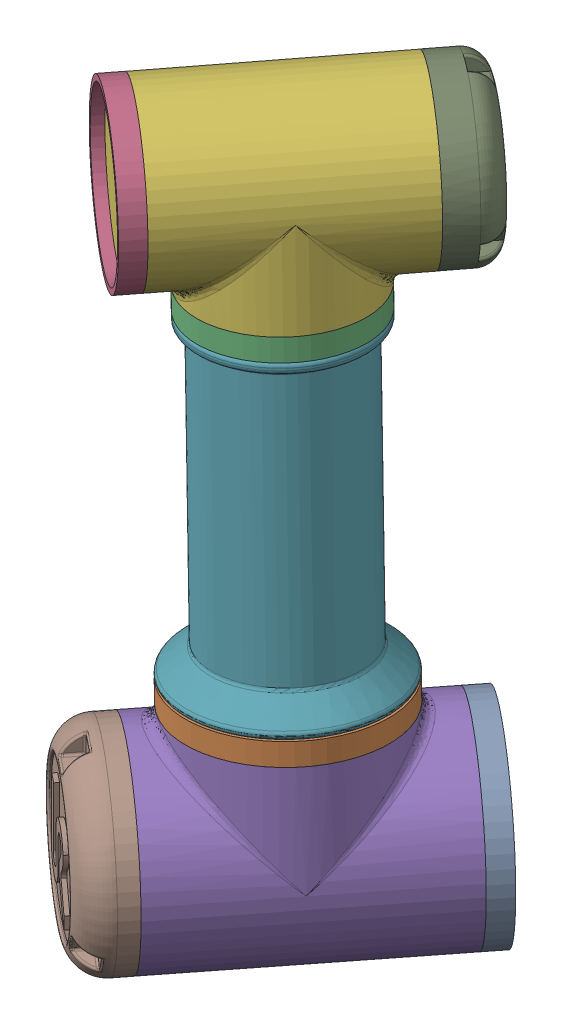
SolidWorks assembly Arm1, configuration Default. Lengths in mm.
Overall size (169.85 344.25 189.73).
9 component instances, 7 part files, 15 mates.
Components (placement in the parent):
- size 2 flange-1: size 2 flange [Default] at (9.7275 181.3176 149.0441) x (-0.785699 0.067901 -0.614872) z (-0.053473 -0.997692 -0.041847) size (90 10 90)
- size 2 flange-2: size 2 flange [Default] at (-31.9175 231.0523 193.9124) x (-0.996208 -0.078792 0.036901) z (-0.031709 -0.066154 -0.997305) size (90 10 90)
- size 1 flange-1: size 1 flange [Default] at (-44.2326 382.2457 184.2748) x (0.850464 0.035819 -0.524812) z (0.519756 0.096444 0.848854) size (75 10 75)
- size 1 flange-2: size 1 flange [Default] at (-85.0209 435.0277 228.5396) x (-0.038648 -0.998852 -0.028288) z (0.792815 -0.047883 0.607579) size (75 10 75)
- shoulder - base  1-1: shoulder - base  1 [Default] at (12.8089 181.3176 145.1066) x (-0.081021 0.994694 -0.063405) z (0.783337 0.102881 0.613024) size (100 122 90)
- size 1 shoulder-1: size 1 shoulder [Default] at (-81.9797 435.0225 224.5709) x (-0.081021 0.994694 -0.063405) z (-0.78961 -0.102876 -0.604923) size (85.5 105 75)
- Upper arm-1: Upper arm [Default] at (-32.3226 236.0258 193.5953) x (-0.452157 -0.093372 -0.887038) z (0.888251 0.043199 -0.457323) size (90 152 90)
- Size 2 Cap-1: Size 2 Cap [Default] at (-62.3789 181.3176 241.1835) x (0.787022 -0.035399 0.615908) z (-0.027877 -0.999373 -0.021816) size (90 23 90)
- Size 1 Cap-1: Size 1 Cap [Default] at (-18.1149 434.9118 141.2265) x (-0.79161 -0.074291 -0.606494) z (0.058329 -0.997236 0.046021) size (75 23.29 75.06)
Mates (geometry in assembly coordinates):
- Concentric4: concentric anti-aligned: cylinder of shoulder - base  1-1 through (9.7275 181.3176 149.0441) axis (0.616294 0 -0.787516) radius 42.5; cylinder of size 2 flange-1 through (15.8904 181.3176 141.169) axis (-0.616294 0 0.787516) radius 45
- Concentric61: concentric aligned: cylinder of shoulder - base  1-1 through (-31.9175 231.0523 193.9124) axis (0.081021 -0.994694 0.063405) radius 45; cylinder of size 2 flange-2 through (-32.7277 240.9992 193.2783) axis (0.081021 -0.994694 0.063405) radius 45
- Coincident5: coincident anti-aligned: plane of shoulder - base  1-1 through (-31.9175 231.0523 193.9124) normal (-0.081021 0.994694 -0.063405); plane of size 2 flange-2 through (-31.9175 231.0523 193.9124) normal (0.081021 -0.994694 0.063405)
- Concentric7: concentric anti-aligned: cylinder of size 2 flange-2 through (-31.0789 220.7572 194.5686) axis (-0.081021 0.994694 -0.063405) radius 42.5; cylinder of Upper arm-1 through (-32.7277 240.9992 193.2783) axis (0.081021 -0.994694 0.063405) radius 42.5
- Concentric62: concentric aligned: cylinder of Upper arm-1 through (-44.6377 387.2192 183.9578) axis (0.081021 -0.994694 0.063405) radius 35; cylinder of size 1 flange-1 through (-45.0428 392.1927 183.6407) axis (0.081021 -0.994694 0.063405) radius 37.5
- Coincident10: coincident anti-aligned: plane of Upper arm-1 through (-44.2326 382.2457 184.2748) normal (-0.081021 0.994694 -0.063405); plane of size 1 flange-1 through (-44.2326 382.2457 184.2748) normal (0.081021 -0.994694 0.063405)
- Concentric64: concentric anti-aligned: cylinder of size 1 shoulder-1 through (-44.6377 387.2192 183.9578) axis (-0.081021 0.994694 -0.063405) radius 35; cylinder of size 1 flange-1 through (-45.0428 392.1927 183.6407) axis (0.081021 -0.994694 0.063405) radius 35
- Concentric651: concentric aligned: cylinder of size 1 shoulder-1 through (-78.9385 435.0172 220.6021) axis (-0.608236 0.001054 0.793755) radius 35; cylinder of size 1 flange-2 through (-78.9385 435.0172 220.6021) axis (-0.608236 0.001054 0.793755) radius 37.5
- Coincident13: coincident anti-aligned: plane of size 1 shoulder-1 through (-78.9385 435.0172 220.6021) normal (-0.608236 0.001054 0.793755); plane of size 1 flange-2 through (-78.9385 435.0172 220.6021) normal (0.608236 -0.001054 -0.793755)
- Coincident9: coincident anti-aligned: plane of shoulder - base  1-1 through (-32.3226 236.0258 193.5953) normal (-0.081021 0.994694 -0.063405); plane of Upper arm-1 through (-32.3226 236.0258 193.5953) normal (0.081021 -0.994694 0.063405)
- Coincident31: coincident anti-aligned: plane of shoulder - base  1-1 through (-62.3789 181.3176 241.1835) normal (-0.616294 0 0.787516); plane of Size 2 Cap-1 through (-62.3789 181.3176 241.1835) normal (0.616294 0 -0.787516)
- Concentric84: concentric anti-aligned: circle of shoulder - base  1-1; cylinder of Size 2 Cap-1 through (-76.5537 181.3176 259.2964) axis (0.616294 0 -0.787516) radius 45
- Coincident12: coincident anti-aligned: plane of Upper arm-1 through (-44.6377 387.2192 183.9578) normal (-0.081021 0.994694 -0.063405); plane of size 1 shoulder-1 through (-44.6377 387.2192 183.9578) normal (0.081021 -0.994694 0.063405)
- Concentric90: concentric anti-aligned: circle of size 1 shoulder-1; cylinder of Size 1 Cap-1 through (-4.1255 434.8875 122.9702) axis (-0.608236 0.001054 0.793755) radius 37.5
- Coincident36: coincident anti-aligned: plane of size 1 shoulder-1 through (-18.1149 434.9118 141.2265) normal (0.608236 -0.001054 -0.793755); plane of Size 1 Cap-1 through (-18.1149 434.9118 141.2265) normal (-0.608236 0.001054 0.793755)
